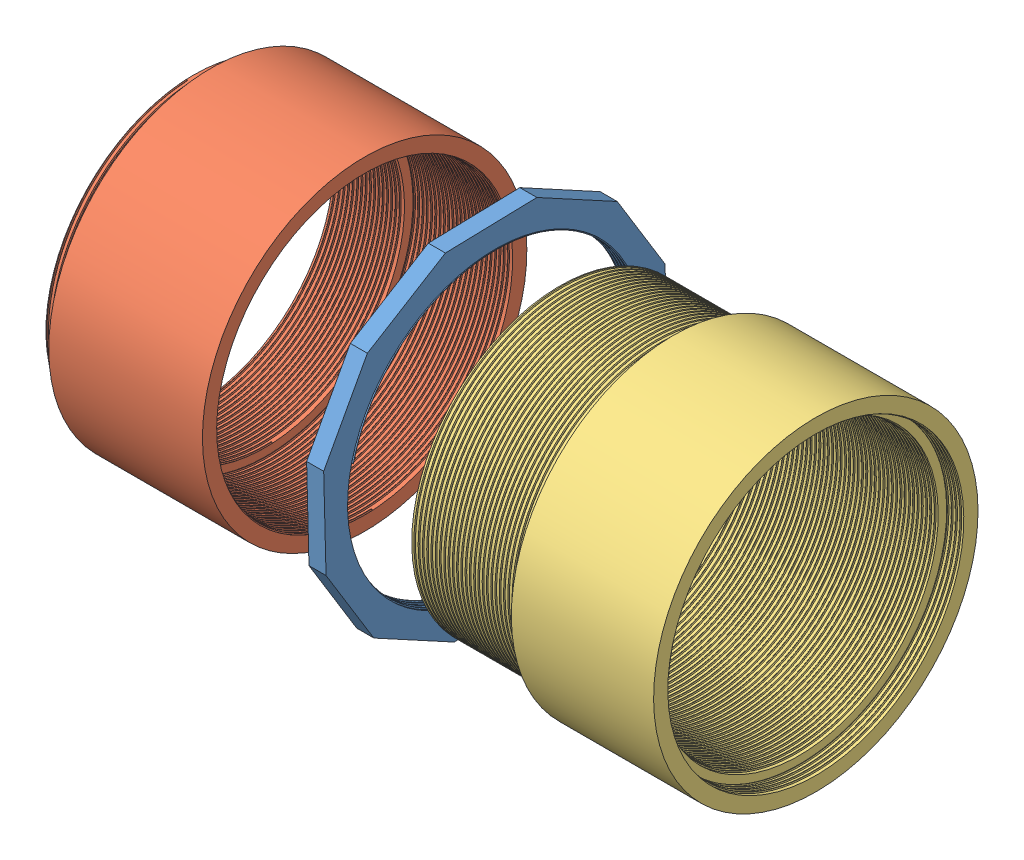
SolidWorks assembly BAGUE complète, configuration Défaut. Lengths in mm.
Overall size (109.55 74.92 74.92).
3 component instances, 3 part files, 4 mates.
Components (placement in the parent):
- Ecrou-1: Ecrou [Défaut] at (-11.4634 0.5228 53.8344) x (1 0 0) z (0 -0.233758 -0.972295) size (3.28 62.12 62.12)
- bague bas-1: bague bas [Défaut] at (-61.4634 0.5228 53.8344) x (1 0 0) z (0 -0.998666 -0.051636) size (30.28 57 57)
- Bague haut-1: Bague haut [Défaut] at (2.8088 0.5228 53.8344) x (1 0 0) z (0 0.075496 0.997146) size (45.28 57 57)
Mates (geometry in assembly coordinates):
- Coaxiale1: concentric aligned: cylinder of bague bas-1 through (-31.4634 0.5228 53.8344) axis (-1 0 0) radius 28.5; cylinder of Bague haut-1 through (47.8088 0.5228 53.8344) axis (-1 0 0) radius 28.5
- Coaxiale2: concentric anti-aligned: circle of Ecrou-1; circle of Bague haut-1
- DistanceLimite1: limit distance = 20 mm anti-aligned: plane of Ecrou-1 through (-11.4634 0.5228 53.8344) normal (-1 0 0); plane of bague bas-1 through (-31.4634 0.5228 53.8344) normal (1 0 0)
- DistanceLimite2: limit distance = 31.2721 mm anti-aligned: plane of Ecrou-1 through (-8.4634 0.5228 53.8344) normal (1 0 0); plane of Bague haut-1 through (22.8088 0.5228 53.8344) normal (-1 0 0)
